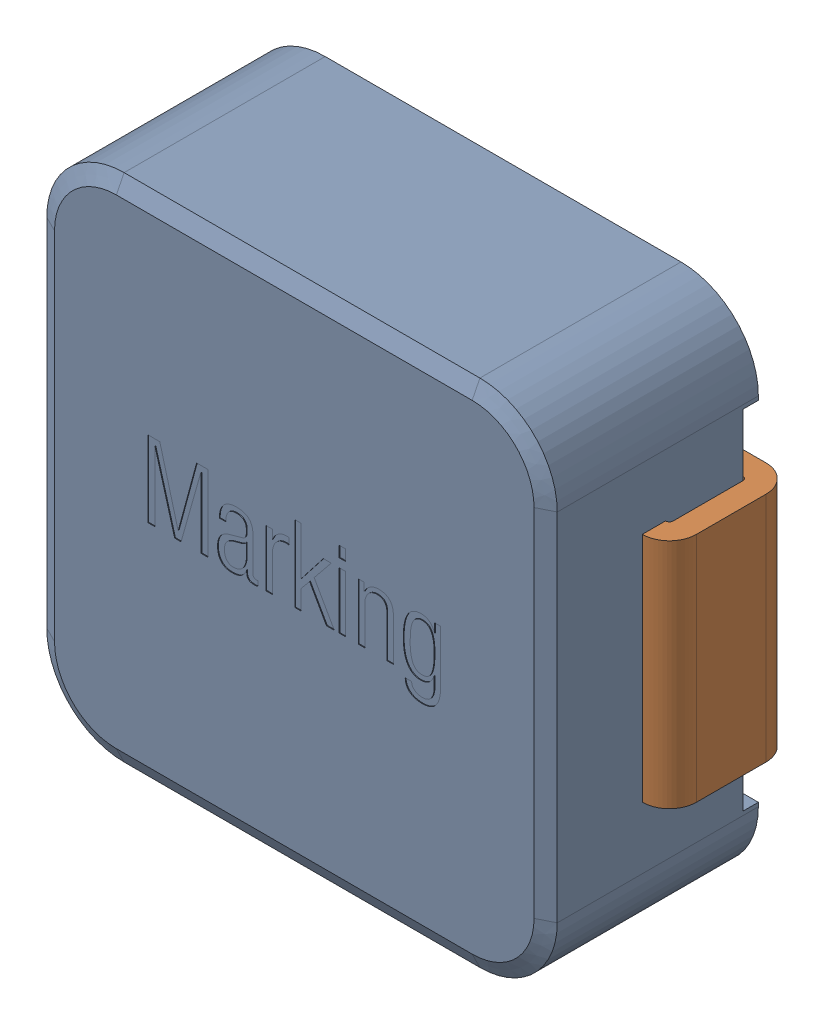
SolidWorks assembly L1, configuration 默认. Lengths in mm.
Overall size (7.3 6.6 2.8).
3 component instances, 2 part files, 0 mates.
Components (placement in the parent):
- WE-LHMI-7030_rev1-1: WE-LHMI-7030_rev1 [默认] at (33.7726 17.3228 0.1) size (7.3 6.6 2.8)
  - base-1: base [默认] at origin size (6.6 6.6 2.7)
  - pin-1: pin [默认] at origin size (7.3 3 1.6)
